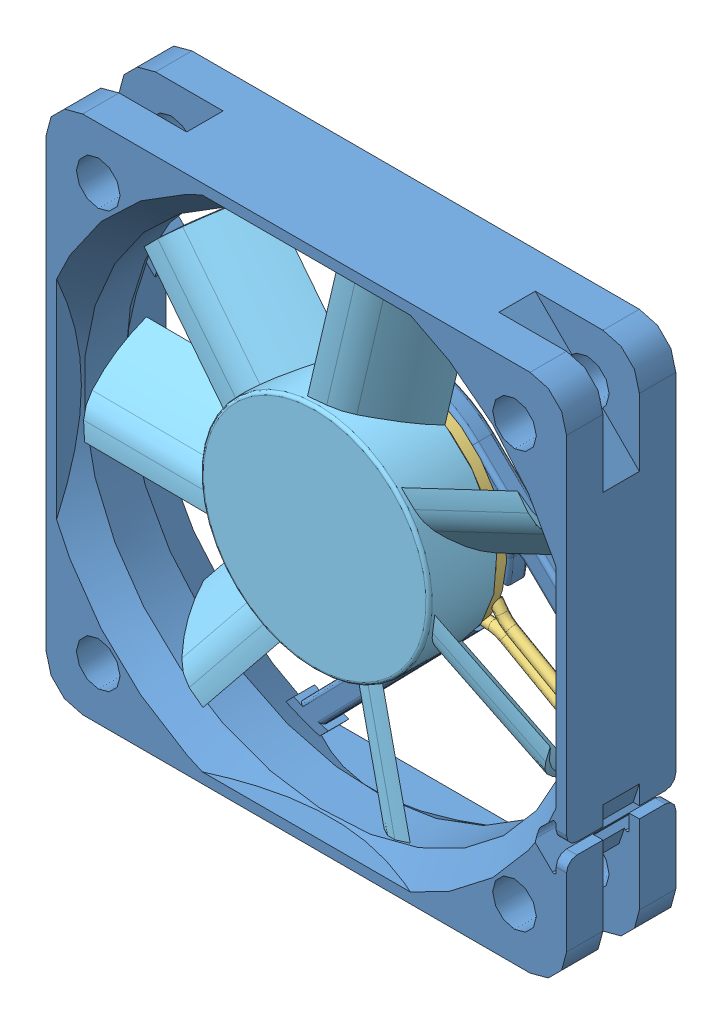
SolidWorks assembly Cooler 50x50x10.5 detailed SBORKA, configuration Default. Lengths in mm.
Overall size (56.44 55.29 12.93).
5 component instances, 5 part files, 9 mates.
Components (placement in the parent):
- Cooler 50x50x10.5 body-1: Cooler 50x50x10.5 body [Default] at (41.3687 25.409 14.5896) size (50 50 12.93)
- Sticker SUNON-1: Sticker SUNON [Default] at (41.3687 25.409 14.5896) x (-1 0 0) z (0 0 -1) size (18 18 0.07)
- Cooler pcb-1: Cooler pcb [Default] at (41.3687 25.409 17.5896) x (-0.870378 0.492384 0) z (0 0 -1) size (37.75 21.5 5.61)
- Cooler Motor-1: Cooler Motor [Default] at (41.3687 25.409 14.5896) x (0.999688 -0.024998 0) z (0 0 1) size (18 18 8.5)
- Cooler Blades-1: Cooler Blades [Default] at (41.3687 25.409 17.7896) x (-0.973565 0.228411 0) z (0 0 1) size (46 46 8.5)
Mates (geometry in assembly coordinates):
- Совпадение1: coincident: plane of Cooler 50x50x10.5 body-1 through (41.3687 25.409 16.5896) normal (0 0 1); plane of Cooler pcb-1 through (41.3687 25.409 16.5896) normal (0 0 -1)
- Концентричный1: concentric: cylinder of Cooler 50x50x10.5 body-1 through (41.3687 25.409 25.0896) axis (0 0 -1) radius 2.75; cylinder of Cooler pcb-1 through (41.3687 25.409 17.5896) axis (0 0 -1) radius 3
- Совпадение2: coincident: plane of Cooler 50x50x10.5 body-1 through (62.8687 46.909 14.5896) normal (0 0 -1); plane of Sticker SUNON-1 through (41.3687 25.409 14.5896) normal (0 0 1)
- Параллельность1: parallel: plane of Cooler 50x50x10.5 body-1 through (19.8687 50.409 25.0896) normal (0 1 0); line of Sticker SUNON-1 through (32.5869 27.3787 14.5296) axis (1 0 0)
- Концентричный2: concentric: cylinder of Cooler 50x50x10.5 body-1 through (41.3687 25.409 25.0896) axis (0 0 -1) radius 2.75; cylinder of Sticker SUNON-1 through (41.3687 25.409 14.5396) axis (0 0 1) radius 9
- Концентричный3: concentric: cylinder of Cooler 50x50x10.5 body-1 through (41.3687 25.409 25.0896) axis (0 0 -1) radius 2.75; cylinder of Cooler Motor-1 through (41.3687 25.409 17.5896) axis (0 0 -1) radius 2.75
- Совпадение4: coincident: plane of Cooler 50x50x10.5 body-1 through (62.8687 46.909 14.5896) normal (0 0 -1); plane of Cooler Motor-1 through (41.3687 25.409 14.5896) normal (0 0 -1)
- Концентричный4: concentric: cylinder of Cooler Blades-1 through (41.3687 25.409 15.7896) axis (0 0 1) radius 0.7; cylinder of Cooler Motor-1 through (41.3687 25.409 15.5896) axis (0 0 1) radius 0.75
- Расстояние1: distance = 0.8 mm: plane of Cooler Blades-1 through (41.3687 25.409 24.2896) normal (0 0 1); plane of Cooler 50x50x10.5 body-1 through (62.8687 46.909 25.0896) normal (0 0 1)
